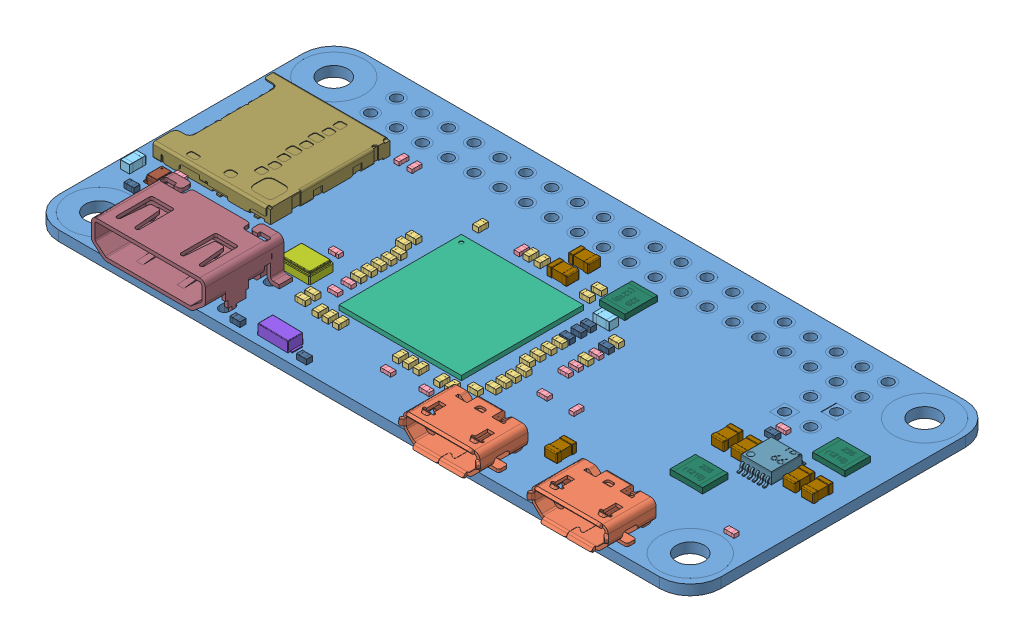
SolidWorks assembly RapberryPiZero, configuration Default. Lengths in mm.
Overall size (65 4.45 31.23).
81 component instances, 15 part files, 154 mates.
Components (placement in the parent):
- Raspberry_pizero_PCB-1: Raspberry_pizero_PCB [Default] at (-51.2564 20.0966 13.0542) size (65 1 30)
- Micro USB_input_female (short)-SMT-1: Micro USB_input_female (short)-SMT [Default] at (-42.3564 22.3216 26.5042) size (7.98 2.94 5.43)
- Micro USB_input_female (short)-SMT-2: Micro USB_input_female (short)-SMT [Default] at (-29.7564 22.3216 26.5042) size (7.98 2.94 5.43)
- 0204 - Capacitor-1: 0204 - Capacitor [Default] at (-62.4121 21.3466 11.2398) size (1 0.5 0.6)
- 0204 - Capacitor-2: 0204 - Capacitor [Default] at (-62.4121 21.3466 12.2528) size (1 0.5 0.6)
- 0204 - Capacitor-3: 0204 - Capacitor [Default] at (-61.8122 21.3466 13.3136) size (1 0.5 0.6)
- 0204 - Capacitor-4: 0204 - Capacitor [Default] at (-61.8122 21.3466 14.2646) size (1 0.5 0.6)
- 0204 - Capacitor-5: 0204 - Capacitor [Default] at (-61.8122 21.3466 15.241) size (1 0.5 0.6)
- 0204 - Capacitor-6: 0204 - Capacitor [Default] at (-61.8122 21.3466 16.2144) size (1 0.5 0.6)
- 0204 - Capacitor-7: 0204 - Capacitor [Default] at (-61.8122 21.3466 17.2416) size (1 0.5 0.6)
- 0204 - Capacitor-8: 0204 - Capacitor [Default] at (-62.5919 21.3466 20.9695) size (1 0.5 0.6)
- 0204 - Capacitor-9: 0204 - Capacitor [Default] at (-62.5919 21.3466 21.919) size (1 0.5 0.6)
- 0204 - Capacitor-10: 0204 - Capacitor [Default] at (-60.4584 21.3466 22.3712) x (0 0 1) z (-1 0 0) size (1 0.5 0.6)
- 0204 - Capacitor-11: 0204 - Capacitor [Default] at (-60.0807 21.3466 22.3712) x (0 0 -1) z (1 0 0) size (1 0.5 0.6)
- 0204 - Capacitor-12: 0204 - Capacitor [Default] at (-59.0466 21.3466 22.3712) x (0 0 -1) z (1 0 0) size (1 0.5 0.6)
- 0204 - Capacitor-13: 0204 - Capacitor [Default] at (-52.6496 21.3466 22.316) x (0 0 1) z (-1 0 0) size (1 0.5 0.6)
- 0204 - Capacitor-14: 0204 - Capacitor [Default] at (-52.25 21.3466 22.316) x (0 0 -1) z (1 0 0) size (1 0.5 0.6)
- 0204 - Capacitor-15: 0204 - Capacitor [Default] at (-51.2398 21.3466 22.316) x (0 0 -1) z (1 0 0) size (1 0.5 0.6)
- 0204 - Capacitor-16: 0204 - Capacitor [Default] at (-49.1841 21.3466 22.316) x (0 0 -1) z (1 0 0) size (1 0.5 0.6)
- 0204 - Capacitor-17: 0204 - Capacitor [Default] at (-48.1448 21.3466 22.316) x (0 0 -1) z (1 0 0) size (1 0.5 0.6)
- 0204 - Capacitor-18: 0204 - Capacitor [Default] at (-46.475 21.3466 21.113) size (1 0.5 0.6)
- 0204 - Capacitor-19: 0204 - Capacitor [Default] at (-45.7322 21.3466 20.0663) size (1 0.5 0.6)
- 0204 - Capacitor-20: 0204 - Capacitor [Default] at (-45.7322 21.3466 19.0675) size (1 0.5 0.6)
- 0204 - Capacitor-21: 0204 - Capacitor [Default] at (-45.7322 21.3466 18.1249) size (1 0.5 0.6)
- 0204 - Capacitor-22: 0204 - Capacitor [Default] at (-45.7322 21.3466 17.1095) size (1 0.5 0.6)
- 0204 - Capacitor-23: 0204 - Capacitor [Default] at (-46.3457 21.3466 16.1412) size (1 0.5 0.6)
- 0204 - Capacitor-24: 0204 - Capacitor [Default] at (-46.3457 21.3466 15.1229) size (1 0.5 0.6)
- 0204 - Capacitor-25: 0204 - Capacitor [Default] at (-46.3457 21.3466 14.0197) size (1 0.5 0.6)
- 0204 - Capacitor-26: 0204 - Capacitor [Default] at (-46.3457 21.3466 12.9589) size (1 0.5 0.6)
- 0204 - Capacitor-27: 0204 - Capacitor [Default] at (-43.6156 21.3466 13.1418) size (1 0.5 0.6)
- 0204 - Capacitor-28: 0204 - Capacitor [Default] at (-43.6156 21.3466 10.1424) size (1 0.5 0.6)
- 0204 - Capacitor-29: 0204 - Capacitor [Default] at (-48.9117 21.3466 7.6917) size (1 0.5 0.6)
- 0204 - Capacitor-30: 0204 - Capacitor [Default] at (-55.4926 21.3466 7.2526) x (0 0 -1) z (1 0 0) size (1 0.5 0.6)
- 0204 - Capacitor-31: 0204 - Capacitor [Default] at (-53.7932 21.3466 7.2526) x (0 0 1) z (-1 0 0) size (1 0.5 0.6)
- 0204 - Capacitor-32: 0204 - Capacitor [Default] at (-59.8477 21.3466 7.2526) x (0 0 1) z (-1 0 0) size (1 0.5 0.6)
- 0204- Resistor-15: 0204- Resistor [Default] at (-43.6109 21.4522 15.4193) x (-1 0 0) z (0 -1 0) size (0.99 0.51 0.36)
- 0204- Resistor-14: 0204- Resistor [Default] at (-43.6109 21.4522 14.4127) x (-1 0 0) z (0 -1 0) size (0.99 0.51 0.36)
- 0204- Resistor-13: 0204- Resistor [Default] at (-43.6109 21.4522 12.4047) x (-1 0 0) z (0 -1 0) size (0.99 0.51 0.36)
- 0204- Resistor-4: 0204- Resistor [Default] at (-42.6936 21.4522 18.4076) x (-1 0 0) z (0 -1 0) size (0.99 0.51 0.36)
- 0204- Resistor-5: 0204- Resistor [Default] at (-39.831 21.4522 18.1462) x (0 0 1) z (0 -1 0) size (0.99 0.51 0.36)
- 0204- Resistor-7: 0204- Resistor [Default] at (-61.8169 21.4522 19.8533) x (-1 0 0) z (0 -1 0) size (0.99 0.51 0.36)
- 0204- Resistor-8: 0204- Resistor [Default] at (-61.8169 21.4522 18.5178) x (-1 0 0) z (0 -1 0) size (0.99 0.51 0.36)
- 0204- Resistor-9: 0204- Resistor [Default] at (-79.148 21.4522 17.7279) x (-1 0 0) z (0 -1 0) size (0.99 0.51 0.36)
- 0204- Resistor-10: 0204- Resistor [Default] at (-56.0985 21.4522 7.2479) x (0 0 -1) z (0 -1 0) size (0.99 0.51 0.36)
- 0204- Resistor-11: 0204- Resistor [Default] at (-28.0827 21.4522 9.5819) x (-1 0 0) z (0 -1 0) size (0.99 0.51 0.36)
- 0204- Resistor-12: 0204- Resistor [Default] at (-21.8613 21.4522 20.9026) x (-1 0 0) z (0 -1 0) size (0.99 0.51 0.36)
- CAP-0306-1: CAP-0306 [Default] at (-45.8903 21.4966 8.7634) size (1.6 0.8 0.9)
- CAP-0306-2: CAP-0306 [Default] at (-82.0031 21.4966 19.0464) x (0 0 1) z (-1 0 0) size (1.6 0.8 0.9)
- Raspberry_pizero_BCM2835 with VC4-2: Raspberry_pizero_BCM2835 with VC4 [Default] at (-54.1608 21.5466 15.1238) x (1 0 0) z (0 0 -1) size (12 0.65 12)
- Crystal 3.4x2.4mm-1: Crystal 3.4x2.4mm [Default] at (-65.3089 21.0966 19.2633) size (3.2 1 2.4)
- 0204- Resistor-16: 0204- Resistor [Default] at (-68.4329 21.4522 5.4384) x (0 0 1) z (0 -1 0) size (0.99 0.51 0.36)
- 0204- Resistor-17: 0204- Resistor [Default] at (-69.7255 21.4522 5.4384) x (0 0 1) z (0 -1 0) size (0.99 0.51 0.36)
- 0204- Resistor-18: 0204- Resistor [Default] at (-65.0626 21.4522 16.5355) x (1 0 0) z (0 -1 0) size (0.99 0.51 0.36)
- 32,768 Khz Crystal-1: 32,768 Khz Crystal [Default] at (-60.5154 21.1428 26.5473) x (0.999848 -0.017452 0) z (0 0 1) size (3.4 1.03 1.5)
- 0805- Capacitor-1: 0805- Capacitor [Default] at (-51.9496 21.9966 5.2384) x (1 0 0) z (0 -1 0) size (2 1.25 0.9)
- 0805- Capacitor-2: 0805- Capacitor [Default] at (-51.9496 21.9966 7.3589) x (1 0 0) z (0 -1 0) size (2 1.25 0.9)
- 0805- Capacitor-3: 0805- Capacitor [Default] at (-37.009 21.9966 22.5384) x (0 0 -1) z (0 -1 0) size (2 1.25 0.9)
- 0805- Capacitor-4: 0805- Capacitor [Default] at (-29.8247 21.9966 13.3538) x (0 0 1) z (0 -1 0) size (2 1.25 0.9)
- 0805- Capacitor-5: 0805- Capacitor [Default] at (-27.9052 21.9966 13.3538) x (0 0 -1) z (0 -1 0) size (2 1.25 0.9)
- 0805- Capacitor-6: 0805- Capacitor [Default] at (-22.8003 21.9966 13.3538) x (0 0 -1) z (0 -1 0) size (2 1.25 0.9)
- 0805- Capacitor-7: 0805- Capacitor [Default] at (-20.9924 21.9966 13.3538) x (0 0 -1) z (0 -1 0) size (2 1.25 0.9)
- 0204- Resistor-19: 0204- Resistor [Default] at (-48.8769 21.4522 23.8207) x (1 0 0) z (0 -1 0) size (0.99 0.51 0.36)
- 0204- Resistor-20: 0204- Resistor [Default] at (-52.4165 21.4522 24.0419) x (1 0 0) z (0 -1 0) size (0.99 0.51 0.36)
- 0204 - Capacitor-33: 0204 - Capacitor [Default] at (-47.1199 21.3466 23.926) x (0 0 1) z (-1 0 0) size (1 0.5 0.6)
- 0204 - Capacitor Brown-34: 0204 - Capacitor Brown [Default] at (-57.5817 21.3466 26.803) size (1 0.5 0.6)
- 0204 - Capacitor Brown-35: 0204 - Capacitor Brown [Default] at (-64.0312 21.3466 26.8794) size (1 0.5 0.6)
- 0204 - Capacitor Brown-36: 0204 - Capacitor Brown [Default] at (-46.3457 21.3466 12.214) size (1 0.5 0.6)
- 0204 - Capacitor Brown-37: 0204 - Capacitor Brown [Default] at (-46.3457 21.3466 11.0963) size (1 0.5 0.6)
- 0204 - Capacitor Brown-38: 0204 - Capacitor Brown [Default] at (-46.3457 21.3466 10.1566) size (1 0.5 0.6)
- 0204 - Capacitor Brown-39: 0204 - Capacitor Brown [Default] at (-43.6156 21.3466 11.1151) size (1 0.5 0.6)
- 0204 - Capacitor Brown-40: 0204 - Capacitor Brown [Default] at (-28.0874 21.3466 10.3236) size (1 0.5 0.6)
- 0204 - Capacitor Brown-41: 0204 - Capacitor Brown [Default] at (-80.6197 21.3466 20.6997) size (1 0.5 0.6)
- 0204- Resistor-21: 0204- Resistor [Default] at (-78.9105 21.4522 21.1554) x (1 0 0) z (0 -1 0) size (0.99 0.51 0.36)
- 6-Pin SOT-1: 6-Pin SOT [Default] at (-79.714 21.0966 19.2138) x (0 0 1) z (0 1 0) size (1.5 1.84 0.95)
- micro sd molex-1: micro sd molex [Default] at (-74.7768 21.6766 -33.0961) x (0 0 1) z (0 1 0) size (11.95 11.4 1.45)
- hdmi type C-1: hdmi type C [Default] at (-71.3564 22.9466 28.6542) size (12.9 4.05 7.7)
- Voltage Regulator 3x3mm 12-Pin-1: Voltage Regulator 3x3mm 12-Pin [Default] at (-23.6842 21.0966 12.6105) x (1 0 0) z (0 1 0) size (3 4.1 1.2)
- 1210 inductor-1: 1210 inductor [Default] at (-46.4963 21.0916 6.3909) x (0 0 1) z (0 1 0) size (3.26 2.86 0.75)
- 1210 inductor-2: 1210 inductor [Default] at (-22.7405 21.0916 9.2394) x (1 0 0) z (0 1 0) size (3.26 2.86 0.75)
- 1210 inductor-3: 1210 inductor [Default] at (-28.2854 21.0916 17.6682) x (1 0 0) z (0 1 0) size (3.26 2.86 0.75)
- 0204 - Capacitor-34: 0204 - Capacitor [Default] at (-48.9117 21.3466 6.5273) size (1 0.5 0.6)
Mates (geometry in assembly coordinates):
- Coincident1: coincident: plane of Raspberry_pizero_PCB-1 through (-80.7564 21.0966 1.0542) normal (0 1 0); plane of Micro USB_input_female (short)-SMT-1 through (-46.4124 21.0966 24.1966) normal (0 -1 0)
- Coincident2: coincident: plane of Raspberry_pizero_PCB-1 through (-80.7564 21.0966 1.0542) normal (0 1 0); plane of Micro USB_input_female (short)-SMT-2 through (-33.8124 21.0966 24.1966) normal (0 -1 0)
- Coincident3: coincident: plane of 0204 - Capacitor-13 through (-52.9516 21.5916 22.316) normal (0 1 0); plane of 0204 - Capacitor-14 through (-51.948 21.5916 22.316) normal (0 1 0)
- Coincident4: coincident: plane of 0204 - Capacitor-14 through (-51.948 21.5916 22.316) normal (0 1 0); plane of 0204 - Capacitor-15 through (-50.9378 21.5916 22.316) normal (0 1 0)
- Coincident5: coincident: plane of 0204 - Capacitor-15 through (-50.9378 21.5916 22.316) normal (0 1 0); plane of 0204 - Capacitor-16 through (-48.8821 21.5916 22.316) normal (0 1 0)
- Coincident6: coincident: plane of 0204 - Capacitor-16 through (-48.8821 21.5916 22.316) normal (0 1 0); plane of 0204 - Capacitor-17 through (-47.8428 21.5916 22.316) normal (0 1 0)
- Coincident7: coincident: plane of 0204 - Capacitor-17 through (-47.8428 21.5916 22.316) normal (0 1 0); plane of 0204 - Capacitor-18 through (-46.475 21.5916 21.415) normal (0 1 0)
- Coincident8: coincident: plane of 0204 - Capacitor-18 through (-46.475 21.5916 21.415) normal (0 1 0); plane of 0204 - Capacitor-19 through (-45.7322 21.5916 20.3683) normal (0 1 0)
- Coincident9: coincident: plane of 0204 - Capacitor-19 through (-45.7322 21.5916 20.3683) normal (0 1 0); plane of 0204 - Capacitor-20 through (-45.7322 21.5916 19.3695) normal (0 1 0)
- Coincident10: coincident: plane of 0204 - Capacitor-20 through (-45.7322 21.5916 19.3695) normal (0 1 0); plane of 0204 - Capacitor-21 through (-45.7322 21.5916 18.4269) normal (0 1 0)
- Coincident11: coincident: plane of 0204 - Capacitor-21 through (-45.7322 21.5916 18.4269) normal (0 1 0); plane of 0204 - Capacitor-22 through (-45.7322 21.5916 17.4115) normal (0 1 0)
- Coincident12: coincident: plane of 0204 - Capacitor-22 through (-45.7322 21.5916 17.4115) normal (0 1 0); plane of 0204 - Capacitor-23 through (-46.3457 21.5916 16.4432) normal (0 1 0)
- Coincident13: coincident: plane of 0204 - Capacitor-23 through (-46.3457 21.5916 16.4432) normal (0 1 0); plane of 0204 - Capacitor-24 through (-46.3457 21.5916 15.4249) normal (0 1 0)
- Coincident14: coincident: plane of 0204 - Capacitor-24 through (-46.3457 21.5916 15.4249) normal (0 1 0); plane of 0204 - Capacitor-25 through (-46.3457 21.5916 14.3217) normal (0 1 0)
- Coincident15: coincident: plane of 0204 - Capacitor-25 through (-46.3457 21.5916 14.3217) normal (0 1 0); plane of 0204 - Capacitor-26 through (-46.3457 21.5916 13.2609) normal (0 1 0)
- Coincident16: coincident: plane of 0204 - Capacitor-26 through (-46.3457 21.5916 13.2609) normal (0 1 0); plane of 0204 - Capacitor-27 through (-43.6156 21.5916 13.4438) normal (0 1 0)
- Coincident17: coincident: plane of 0204 - Capacitor-27 through (-43.6156 21.5916 13.4438) normal (0 1 0); plane of 0204 - Capacitor-28 through (-43.6156 21.5916 10.4444) normal (0 1 0)
- Coincident18: coincident: plane of 0204 - Capacitor-28 through (-43.6156 21.5916 10.4444) normal (0 1 0); plane of 0204 - Capacitor-29 through (-48.9117 21.5916 7.9937) normal (0 1 0)
- Coincident19: coincident: plane of 0204 - Capacitor-29 through (-48.9117 21.5916 7.9937) normal (0 1 0); plane of 0204 - Capacitor-31 through (-54.0952 21.5916 7.2526) normal (0 1 0)
- Coincident20: coincident: plane of 0204 - Capacitor-30 through (-55.1906 21.5916 7.2526) normal (0 1 0); plane of 0204 - Capacitor-31 through (-54.0952 21.5916 7.2526) normal (0 1 0)
- Coincident21: coincident: plane of 0204 - Capacitor-30 through (-55.1906 21.5916 7.2526) normal (0 1 0); plane of 0204 - Capacitor-32 through (-60.1497 21.5916 7.2526) normal (0 1 0)
- Coincident22: coincident: plane of 0204 - Capacitor-1 through (-62.4121 21.5916 11.5418) normal (0 1 0); plane of 0204 - Capacitor-32 through (-60.1497 21.5916 7.2526) normal (0 1 0)
- Coincident23: coincident: plane of 0204 - Capacitor-1 through (-62.4121 21.5916 11.5418) normal (0 1 0); plane of 0204 - Capacitor-2 through (-62.4121 21.5916 12.5548) normal (0 1 0)
- Coincident24: coincident: plane of 0204 - Capacitor-2 through (-62.4121 21.5916 12.5548) normal (0 1 0); plane of 0204 - Capacitor-3 through (-61.8122 21.5916 13.6156) normal (0 1 0)
- Coincident25: coincident: plane of 0204 - Capacitor-3 through (-61.8122 21.5916 13.6156) normal (0 1 0); plane of 0204 - Capacitor-4 through (-61.8122 21.5916 14.5666) normal (0 1 0)
- Coincident26: coincident: plane of 0204 - Capacitor-4 through (-61.8122 21.5916 14.5666) normal (0 1 0); plane of 0204 - Capacitor-5 through (-61.8122 21.5916 15.543) normal (0 1 0)
- Coincident27: coincident: plane of 0204 - Capacitor-5 through (-61.8122 21.5916 15.543) normal (0 1 0); plane of 0204 - Capacitor-6 through (-61.8122 21.5916 16.5164) normal (0 1 0)
- Coincident28: coincident: plane of 0204 - Capacitor-6 through (-61.8122 21.5916 16.5164) normal (0 1 0); plane of 0204 - Capacitor-7 through (-61.8122 21.5916 17.5436) normal (0 1 0)
- Coincident29: coincident: plane of 0204 - Capacitor-7 through (-61.8122 21.5916 17.5436) normal (0 1 0); plane of 0204 - Capacitor-8 through (-62.5919 21.5916 21.2715) normal (0 1 0)
- Coincident30: coincident: plane of 0204 - Capacitor-8 through (-62.5919 21.5916 21.2715) normal (0 1 0); plane of 0204 - Capacitor-9 through (-62.5919 21.5916 22.221) normal (0 1 0)
- Coincident31: coincident: plane of 0204 - Capacitor-9 through (-62.5919 21.5916 22.221) normal (0 1 0); plane of 0204 - Capacitor-10 through (-60.7604 21.5916 22.3712) normal (0 1 0)
- Coincident32: coincident: plane of 0204 - Capacitor-10 through (-60.7604 21.5916 22.3712) normal (0 1 0); plane of 0204 - Capacitor-11 through (-59.7787 21.5916 22.3712) normal (0 1 0)
- Coincident33: coincident: plane of 0204 - Capacitor-11 through (-59.7787 21.5916 22.3712) normal (0 1 0); plane of 0204 - Capacitor-12 through (-58.7446 21.5916 22.3712) normal (0 1 0)
- Coincident34: coincident: plane of Raspberry_pizero_PCB-1 through (-80.7564 21.0966 1.0542) normal (0 1 0); plane of 0204 - Capacitor-9 through (-62.9669 21.0966 22.219) normal (0 -1 0)
- Coincident35: coincident: plane of 0204 - Capacitor-25 through (-46.8457 21.0966 14.3197) normal (-1 0 0); plane of 0204 - Capacitor-26 through (-46.8457 21.0966 13.2589) normal (-1 0 0)
- Coincident36: coincident: plane of 0204 - Capacitor-24 through (-46.8457 21.0966 15.4229) normal (-1 0 0); plane of 0204 - Capacitor-25 through (-46.8457 21.0966 14.3197) normal (-1 0 0)
- Coincident37: coincident: plane of 0204 - Capacitor-23 through (-46.8457 21.0966 16.4412) normal (-1 0 0); plane of 0204 - Capacitor-24 through (-46.8457 21.0966 15.4229) normal (-1 0 0)
- Coincident38: coincident: plane of 0204 - Capacitor-27 through (-44.1156 21.0966 13.4418) normal (-1 0 0); plane of 0204 - Capacitor-28 through (-44.1156 21.0966 10.4424) normal (-1 0 0)
- Parallel1: parallel: plane of Raspberry_pizero_PCB-1 through (-80.7564 21.0966 -1.9458) normal (0 0 -1); plane of 0204 - Capacitor-30 through (-55.1926 21.0966 7.7526) normal (0 0 1)
- Coincident39: coincident: plane of 0204 - Capacitor-30 through (-55.1926 21.0966 6.7526) normal (0 0 -1); plane of 0204 - Capacitor-31 through (-54.0932 21.0966 6.7526) normal (0 0 -1)
- Coincident40: coincident: plane of 0204 - Capacitor-30 through (-55.1926 21.0966 6.7526) normal (0 0 -1); plane of 0204 - Capacitor-32 through (-60.1477 21.0966 6.7526) normal (0 0 -1)
- Coincident41: coincident: plane of 0204 - Capacitor-1 through (-62.9121 21.0966 11.5398) normal (-1 0 0); plane of 0204 - Capacitor-2 through (-62.9121 21.0966 12.5528) normal (-1 0 0)
- Coincident42: coincident: plane of 0204 - Capacitor-3 through (-62.3122 21.0966 13.6136) normal (-1 0 0); plane of 0204 - Capacitor-4 through (-62.3122 21.0966 14.5646) normal (-1 0 0)
- Coincident43: coincident: plane of 0204 - Capacitor-4 through (-62.3122 21.0966 14.5646) normal (-1 0 0); plane of 0204 - Capacitor-5 through (-62.3122 21.0966 15.541) normal (-1 0 0)
- Coincident44: coincident: plane of 0204 - Capacitor-5 through (-62.3122 21.0966 15.541) normal (-1 0 0); plane of 0204 - Capacitor-6 through (-62.3122 21.0966 16.5144) normal (-1 0 0)
- Coincident45: coincident: plane of 0204 - Capacitor-6 through (-62.3122 21.0966 16.5144) normal (-1 0 0); plane of 0204 - Capacitor-7 through (-62.3122 21.0966 17.5416) normal (-1 0 0)
- Coincident46: coincident: plane of 0204 - Capacitor-8 through (-63.0919 21.0966 21.2695) normal (-1 0 0); plane of 0204 - Capacitor-9 through (-63.0919 21.0966 22.219) normal (-1 0 0)
- Parallel2: parallel: plane of Raspberry_pizero_PCB-1 through (-80.7564 21.0966 28.0542) normal (0 0 1); plane of 0204 - Capacitor-10 through (-60.7584 21.0966 21.8712) normal (0 0 -1)
- Coincident48: coincident: plane of 0204 - Capacitor-10 through (-60.7584 21.0966 22.8712) normal (0 0 1); plane of 0204 - Capacitor-11 through (-59.7807 21.0966 22.8712) normal (0 0 1)
- Coincident49: coincident: plane of 0204 - Capacitor-11 through (-59.7807 21.0966 22.8712) normal (0 0 1); plane of 0204 - Capacitor-12 through (-58.7466 21.0966 22.8712) normal (0 0 1)
- Parallel3: parallel: plane of Raspberry_pizero_PCB-1 through (-80.7564 21.0966 28.0542) normal (0 0 1); plane of 0204 - Capacitor-13 through (-52.9496 21.0966 21.816) normal (0 0 -1)
- Coincident51: coincident: plane of 0204 - Capacitor-13 through (-52.9496 21.0966 22.816) normal (0 0 1); plane of 0204 - Capacitor-14 through (-51.95 21.0966 22.816) normal (0 0 1)
- Coincident52: coincident: plane of 0204 - Capacitor-14 through (-51.95 21.0966 22.816) normal (0 0 1); plane of 0204 - Capacitor-15 through (-50.9398 21.0966 22.816) normal (0 0 1)
- Coincident53: coincident: plane of 0204 - Capacitor-15 through (-50.9398 21.0966 22.816) normal (0 0 1); plane of 0204 - Capacitor-16 through (-48.8841 21.0966 22.816) normal (0 0 1)
- Coincident54: coincident: plane of 0204 - Capacitor-16 through (-48.8841 21.0966 22.816) normal (0 0 1); plane of 0204 - Capacitor-17 through (-47.8448 21.0966 22.816) normal (0 0 1)
- Parallel7: parallel: plane of Raspberry_pizero_PCB-1 through (-80.7564 21.0966 28.0542) normal (0 0 1); plane of CAP-0306-2 through (-82.4531 21.0966 18.2464) normal (0 0 -1)
- Parallel8: parallel: plane of Raspberry_pizero_PCB-1 through (-18.7564 21.0966 25.0542) normal (1 0 0); plane of CAP-0306-1 through (-45.0903 21.0966 9.2134) normal (1 0 0)
- Coincident77: coincident: plane of 0204 - Capacitor-21 through (-46.2322 21.0966 18.4249) normal (-1 0 0); plane of 0204 - Capacitor-22 through (-46.2322 21.0966 17.4095) normal (-1 0 0)
- Coincident78: coincident: plane of 0204 - Capacitor-20 through (-46.2322 21.0966 19.3675) normal (-1 0 0); plane of 0204 - Capacitor-21 through (-46.2322 21.0966 18.4249) normal (-1 0 0)
- Coincident79: coincident: plane of 0204 - Capacitor-19 through (-46.2322 21.0966 20.3663) normal (-1 0 0); plane of 0204 - Capacitor-20 through (-46.2322 21.0966 19.3675) normal (-1 0 0)
- Coincident80: coincident: plane of Micro USB_input_female (short)-SMT-1 through (-39.2364 21.3596 23.1542) normal (0 0 -1); plane of Micro USB_input_female (short)-SMT-2 through (-26.6364 21.3596 23.1542) normal (0 0 -1)
- Distance1: distance = 41.4 mm: moEndPointRef_w of Micro USB_input_female (short)-SMT-1; plane of Raspberry_pizero_PCB-1 through (-83.7564 21.0966 25.0542) normal (-1 0 0)
- Distance3: distance = 0.8 mm: plane of Micro USB_input_female (short)-SMT-1 through (-46.2564 21.0476 28.8542) normal (0 0 1); plane of Raspberry_pizero_PCB-1 through (-80.7564 21.0966 28.0542) normal (0 0 1)
- Distance4: distance = 54 mm: moEndPointRef_w of Micro USB_input_female (short)-SMT-2; plane of Raspberry_pizero_PCB-1 through (-83.7564 21.0966 25.0542) normal (-1 0 0)
- Coincident86: coincident: plane of Raspberry_pizero_PCB-1 through (-80.7564 21.0966 1.0542) normal (0 1 0); plane of Raspberry_pizero_BCM2835 with VC4-2 through (-54.1608 21.0966 15.1238) normal (0 -1 0)
- Parallel10: parallel: plane of Raspberry_pizero_BCM2835 with VC4-2 through (-60.1608 21.0966 9.1238) normal (0 0 -1); plane of Raspberry_pizero_PCB-1 through (-80.7564 21.0966 28.0542) normal (0 0 1)
- Coincident88: coincident: plane of Raspberry_pizero_PCB-1 through (-80.7564 21.0966 1.0542) normal (0 1 0); plane of CAP-0306-1 through (-45.2653 21.0966 9.2134) normal (0 -1 0)
- Coincident89: coincident: plane of 0204- Resistor-7 through (-61.5248 21.0966 19.5993) normal (0 -1 0); plane of 0204- Resistor-8 through (-61.5248 21.0966 18.2638) normal (0 -1 0)
- Coincident90: coincident: plane of Raspberry_pizero_PCB-1 through (-80.7564 21.0966 1.0542) normal (0 1 0); plane of 0204- Resistor-8 through (-61.5248 21.0966 18.2638) normal (0 -1 0)
- Parallel11: parallel: plane of Raspberry_pizero_PCB-1 through (-80.7564 21.0966 28.0542) normal (0 0 1); plane of 0204 - Capacitor-7 through (-61.8122 21.1016 17.8406) normal (0 0 1)
- Coincident92: coincident: plane of 0204 - Capacitor-7 through (-62.3122 21.0966 17.5416) normal (-1 0 0); plane of 0204- Resistor-8 through (-62.3122 21.0966 18.2638) normal (-1 0 0)
- Coincident93: coincident: plane of 0204- Resistor-7 through (-62.3122 21.0966 19.5993) normal (-1 0 0); plane of 0204- Resistor-8 through (-62.3122 21.0966 18.2638) normal (-1 0 0)
- Coincident94: coincident: plane of 0204 - Capacitor-30 through (-55.1926 21.0966 6.7526) normal (0 0 -1); plane of 0204- Resistor-10 through (-55.8445 21.0966 6.7526) normal (0 0 -1)
- Coincident95: coincident: plane of Raspberry_pizero_PCB-1 through (-80.7564 21.0966 1.0542) normal (0 1 0); plane of 0204- Resistor-10 through (-55.8445 21.0966 6.9558) normal (0 -1 0)
- Coincident96: coincident: plane of 0204- Resistor-14 through (-43.903 21.0966 14.1587) normal (0 -1 0); plane of 0204- Resistor-13 through (-43.903 21.0966 12.1507) normal (0 -1 0)
- Coincident97: coincident: plane of 0204- Resistor-15 through (-43.903 21.0966 15.1653) normal (0 -1 0); plane of 0204- Resistor-14 through (-43.903 21.0966 14.1587) normal (0 -1 0)
- Coincident98: coincident: plane of 0204- Resistor-15 through (-43.903 21.0966 15.1653) normal (0 -1 0); plane of 0204- Resistor-4 through (-42.9857 21.0966 18.1536) normal (0 -1 0)
- Coincident99: coincident: plane of Raspberry_pizero_PCB-1 through (-80.7564 21.0966 1.0542) normal (0 1 0); plane of 0204- Resistor-15 through (-43.903 21.0966 15.1653) normal (0 -1 0)
- Coincident101: coincident: plane of 0204- Resistor-5 through (-40.085 21.0966 18.4383) normal (0 -1 0); plane of 0204- Resistor-11 through (-27.7906 21.0966 9.3279) normal (0 -1 0)
- Coincident102: coincident: plane of 0204- Resistor-11 through (-27.7906 21.0966 9.3279) normal (0 -1 0); plane of 0204- Resistor-12 through (-21.5692 21.0966 20.6486) normal (0 -1 0)
- Coincident103: coincident: plane of Raspberry_pizero_PCB-1 through (-80.7564 21.0966 1.0542) normal (0 1 0); plane of Crystal 3.4x2.4mm-1 through (-65.3089 21.0966 19.2633) normal (0 -1 0)
- Parallel12: parallel: plane of Raspberry_pizero_PCB-1 through (-80.7564 21.0966 28.0542) normal (0 0 1); plane of Crystal 3.4x2.4mm-1 through (-66.9089 21.7966 20.4633) normal (0 0 1)
- Coincident104: coincident: plane of Raspberry_pizero_PCB-1 through (-80.7564 21.0966 1.0542) normal (0 1 0); plane of 0204- Resistor-9 through (-78.8559 21.0966 17.4739) normal (0 -1 0)
- Parallel13: parallel: plane of Raspberry_pizero_PCB-1 through (-80.7564 21.0966 28.0542) normal (0 0 1); plane of 0204- Resistor-9 through (-78.2985 21.4532 17.9829) normal (0 0 1)
- Coincident105: coincident: plane of Raspberry_pizero_PCB-1 through (-80.7564 21.0966 1.0542) normal (0 1 0); plane of CAP-0306-2 through (-82.4531 21.0966 19.6714) normal (0 -1 0)
- Coincident106: coincident: plane of 0204 - Capacitor-28 through (-43.1156 21.0966 10.4424) normal (1 0 0); plane of 0204- Resistor-13 through (-43.1156 21.0966 12.1507) normal (1 0 0)
- Coincident107: coincident: plane of 0204 - Capacitor-27 through (-43.1156 21.0966 13.4418) normal (1 0 0); plane of 0204- Resistor-14 through (-43.1156 21.0966 14.1587) normal (1 0 0)
- Parallel14: parallel: plane of Raspberry_pizero_PCB-1 through (-80.7564 21.0966 28.0542) normal (0 0 1); plane of 0204- Resistor-14 through (-42.7614 21.4532 14.6677) normal (0 0 1)
- Coincident110: coincident: plane of 0204- Resistor-15 through (-43.1156 21.0966 15.1653) normal (1 0 0); plane of 0204- Resistor-14 through (-43.1156 21.0966 14.1587) normal (1 0 0)
- Parallel15: parallel: plane of 0204- Resistor-15 through (-43.1156 21.0966 15.1653) normal (1 0 0); plane of 0204- Resistor-4 through (-42.1983 21.0966 18.1536) normal (1 0 0)
- Parallel16: parallel: plane of Raspberry_pizero_PCB-1 through (-80.7564 21.0966 28.0542) normal (0 0 1); plane of 0204- Resistor-5 through (-40.085 21.0966 18.6415) normal (0 0 1)
- Coincident112: coincident: plane of Raspberry_pizero_PCB-1 through (-80.7564 21.0966 1.0542) normal (0 1 0); plane of 0204- Resistor-5 through (-40.085 21.0966 18.4383) normal (0 -1 0)
- Parallel17: parallel: plane of Raspberry_pizero_PCB-1 through (-18.7564 21.0966 25.0542) normal (1 0 0); plane of 0204- Resistor-12 through (-21.366 21.0966 20.6486) normal (1 0 0)
- Parallel18: parallel: plane of 0204- Resistor-11 through (-27.5874 21.0966 9.3279) normal (1 0 0); plane of 0204- Resistor-12 through (-21.366 21.0966 20.6486) normal (1 0 0)
- Coincident115: coincident: plane of Raspberry_pizero_PCB-1 through (-80.7564 21.0966 1.0542) normal (0 1 0); plane of 0204- Resistor-16 through (-68.6869 21.0966 5.1463) normal (0 -1 0)
- Coincident116: coincident: plane of 0204- Resistor-16 through (-68.6879 21.4532 4.5889) normal (0 1 0); plane of 0204- Resistor-17 through (-69.9805 21.4532 4.5889) normal (0 1 0)
- Coincident117: coincident: plane of 0204- Resistor-17 through (-69.9805 21.4532 4.5889) normal (0 1 0); plane of 0204- Resistor-18 through (-65.9121 21.4532 16.7905) normal (0 1 0)
- Coincident118: coincident: plane of 0204- Resistor-16 through (-68.6869 21.0966 5.9337) normal (0 0 1); plane of 0204- Resistor-17 through (-69.9795 21.0966 5.9337) normal (0 0 1)
- Parallel19: parallel: plane of Raspberry_pizero_PCB-1 through (-80.7564 21.0966 -1.9458) normal (0 0 -1); plane of 0204- Resistor-17 through (-69.9795 21.0966 5.9337) normal (0 0 1)
- Parallel20: parallel: plane of Raspberry_pizero_PCB-1 through (-80.7564 21.0966 28.0542) normal (0 0 1); plane of 0204- Resistor-18 through (-65.9121 21.4532 16.7905) normal (0 0 1)
- Coincident120: coincident: plane of Raspberry_pizero_PCB-1 through (-80.7564 21.0966 1.0542) normal (0 1 0); plane of 32,768 Khz Crystal-1 through (-59.5156 21.0966 27.0473) normal (0 -1 0)
- Coincident121: coincident: plane of Raspberry_pizero_PCB-1 through (-80.7564 21.0966 1.0542) normal (0 1 0); plane of 0805- Capacitor-1 through (-52.9496 21.0966 5.8634) normal (0 -1 0)
- Coincident122: coincident: plane of Raspberry_pizero_PCB-1 through (-80.7564 21.0966 1.0542) normal (0 1 0); plane of 0805- Capacitor-2 through (-52.9496 21.0966 7.9839) normal (0 -1 0)
- Coincident123: coincident: plane of Raspberry_pizero_PCB-1 through (-80.7564 21.0966 1.0542) normal (0 1 0); plane of 0805- Capacitor-3 through (-37.634 21.0966 21.5384) normal (0 -1 0)
- Coincident124: coincident: plane of Raspberry_pizero_PCB-1 through (-80.7564 21.0966 1.0542) normal (0 1 0); plane of 0805- Capacitor-4 through (-30.4497 21.0966 12.3538) normal (0 -1 0)
- Coincident125: coincident: plane of Raspberry_pizero_PCB-1 through (-80.7564 21.0966 1.0542) normal (0 1 0); plane of 0805- Capacitor-5 through (-27.2802 21.0966 14.3538) normal (0 -1 0)
- Parallel21: parallel: plane of Raspberry_pizero_PCB-1 through (-80.7564 21.0966 28.0542) normal (0 0 1); plane of 0805- Capacitor-4 through (-29.8247 21.9966 12.3538) normal (0 0 -1)
- Coincident126: coincident: plane of 0805- Capacitor-4 through (-29.8247 21.9966 14.3538) normal (0 0 1); plane of 0805- Capacitor-5 through (-27.9052 21.9966 14.3538) normal (0 0 1)
- Coincident127: coincident: plane of Raspberry_pizero_PCB-1 through (-80.7564 21.0966 1.0542) normal (0 1 0); plane of 0805- Capacitor-6 through (-22.1753 21.0966 14.3538) normal (0 -1 0)
- Coincident128: coincident: plane of Raspberry_pizero_PCB-1 through (-80.7564 21.0966 1.0542) normal (0 1 0); plane of 0805- Capacitor-7 through (-20.3674 21.0966 14.3538) normal (0 -1 0)
- Coincident129: coincident: plane of 0805- Capacitor-5 through (-27.9052 21.9966 14.3538) normal (0 0 1); plane of 0805- Capacitor-6 through (-22.8003 21.9966 14.3538) normal (0 0 1)
- Coincident130: coincident: plane of 0805- Capacitor-6 through (-22.8003 21.9966 14.3538) normal (0 0 1); plane of 0805- Capacitor-7 through (-20.9924 21.9966 14.3538) normal (0 0 1)
- Parallel22: parallel: plane of Raspberry_pizero_PCB-1 through (-80.7564 21.0966 28.0542) normal (0 0 1); plane of 0805- Capacitor-3 through (-37.009 21.9966 21.5384) normal (0 0 -1)
- Coincident131: coincident: plane of 0805- Capacitor-1 through (-50.9496 21.9966 5.2384) normal (1 0 0); plane of 0805- Capacitor-2 through (-50.9496 21.9966 7.3589) normal (1 0 0)
- Parallel23: parallel: plane of Raspberry_pizero_PCB-1 through (-80.7564 21.0966 28.0542) normal (0 0 1); plane of 6-Pin SOT-1 through (-80.214 22.0466 18.4638) normal (0 0 -1)
- Coincident134: coincident: plane of Raspberry_pizero_PCB-1 through (-80.7564 21.0966 1.0542) normal (0 1 0); plane of 6-Pin SOT-1 through (-80.434 21.0966 19.8263) normal (0 -1 0)
- Coincident135: coincident: plane of Raspberry_pizero_PCB-1 through (-80.7564 21.0966 1.0542) normal (0 1 0); plane of micro sd molex-1 through (-71.1444 21.0966 16.7043) normal (0 -1 0)
- Parallel24: parallel: plane of Raspberry_pizero_PCB-1 through (-80.7564 21.0966 -1.9458) normal (0 0 -1); plane of micro sd molex-1 through (-84.5393 22.448 5.3989) normal (0 0 -1)
- Coincident141: coincident: plane of Raspberry_pizero_PCB-1 through (-80.7564 21.0966 1.0542) normal (0 1 0); plane of hdmi type C-1 through (-77.8064 21.0966 20.9542) normal (0 -1 0)
- Distance5: distance = 12.4 mm: moEndPointRef_w of hdmi type C-1; plane of Raspberry_pizero_PCB-1 through (-83.7564 21.0966 25.0542) normal (-1 0 0)
- Distance6: distance = 17.2 mm: moEndPointRef_w of micro sd molex-1; plane of Raspberry_pizero_PCB-1 through (-80.7564 21.0966 28.0542) normal (0 0 1)
- Parallel25: parallel: plane of Raspberry_pizero_PCB-1 through (-80.7564 21.0966 28.0542) normal (0 0 1); plane of hdmi type C-1 through (-71.3564 22.9466 28.6542) normal (0 0 1)
- Distance7: distance = 0.6 mm: plane of hdmi type C-1 through (-71.3564 22.9466 28.6542) normal (0 0 1); plane of Raspberry_pizero_PCB-1 through (-80.7564 21.0966 28.0542) normal (0 0 1)
- Coincident142: coincident: plane of Raspberry_pizero_PCB-1 through (-80.7564 21.0966 1.0542) normal (0 1 0); plane of 0204 - Capacitor Brown-34 through (-57.9567 21.0966 27.103) normal (0 -1 0)
- Coincident143: coincident: plane of 0204 - Capacitor Brown-34 through (-57.5817 21.5916 27.105) normal (0 1 0); plane of 0204 - Capacitor Brown-35 through (-64.0312 21.5916 27.1814) normal (0 1 0)
- Coincident144: coincident: plane of 0204 - Capacitor-18 through (-46.475 21.5916 21.415) normal (0 1 0); plane of 0204 - Capacitor-33 through (-47.4219 21.5916 23.926) normal (0 1 0)
- Parallel26: parallel: plane of Raspberry_pizero_PCB-1 through (-80.7564 21.0966 28.0542) normal (0 0 1); plane of 0204 - Capacitor-33 through (-47.4199 21.0966 23.426) normal (0 0 -1)
- Coincident146: coincident: plane of Raspberry_pizero_PCB-1 through (-80.7564 21.0966 1.0542) normal (0 1 0); plane of 0204- Resistor-19 through (-48.5848 21.0966 24.0747) normal (0 -1 0)
- Coincident147: coincident: plane of Raspberry_pizero_PCB-1 through (-80.7564 21.0966 1.0542) normal (0 1 0); plane of 0204- Resistor-20 through (-52.1244 21.0966 24.2959) normal (0 -1 0)
- Coincident148: coincident: plane of Raspberry_pizero_PCB-1 through (-80.7564 21.0966 1.0542) normal (0 1 0); plane of 0204- Resistor-21 through (-79.2026 21.0966 21.4094) normal (0 -1 0)
- Coincident149: coincident: plane of Raspberry_pizero_PCB-1 through (-80.7564 21.0966 1.0542) normal (0 1 0); plane of 0204 - Capacitor Brown-41 through (-80.9947 21.0966 20.9997) normal (0 -1 0)
- Parallel27: parallel: plane of Raspberry_pizero_PCB-1 through (-80.7564 21.0966 28.0542) normal (0 0 1); plane of 0204- Resistor-21 through (-78.9105 21.4522 21.4094) normal (0 0 1)
- Parallel28: parallel: plane of Raspberry_pizero_PCB-1 through (-80.7564 21.0966 28.0542) normal (0 0 1); plane of 0204 - Capacitor Brown-41 through (-80.6197 21.1016 21.2987) normal (0 0 1)
- Parallel29: parallel: plane of 0204- Resistor-19 through (-49.7264 21.4532 24.0757) normal (0 0 1); plane of 0204- Resistor-20 through (-53.266 21.4532 24.2969) normal (0 0 1)
- Coincident152: coincident: plane of 0204 - Capacitor Brown-34 through (-57.5817 21.5916 27.105) normal (0 1 0); plane of 0204 - Capacitor Brown-39 through (-43.6156 21.5916 11.4171) normal (0 1 0)
- Coincident153: coincident: plane of 0204 - Capacitor Brown-36 through (-46.3457 21.5916 12.516) normal (0 1 0); plane of 0204 - Capacitor Brown-39 through (-43.6156 21.5916 11.4171) normal (0 1 0)
- Coincident154: coincident: plane of 0204 - Capacitor Brown-36 through (-46.3457 21.5916 12.516) normal (0 1 0); plane of 0204 - Capacitor Brown-37 through (-46.3457 21.5916 11.3983) normal (0 1 0)
- Coincident155: coincident: plane of 0204 - Capacitor Brown-37 through (-46.3457 21.5916 11.3983) normal (0 1 0); plane of 0204 - Capacitor Brown-38 through (-46.3457 21.5916 10.4586) normal (0 1 0)
- Coincident156: coincident: plane of 0204 - Capacitor-26 through (-45.8457 21.0966 13.2589) normal (1 0 0); plane of 0204 - Capacitor Brown-36 through (-45.8457 21.0966 12.514) normal (1 0 0)
- Coincident157: coincident: plane of 0204 - Capacitor Brown-36 through (-45.8457 21.0966 12.514) normal (1 0 0); plane of 0204 - Capacitor Brown-37 through (-45.8457 21.0966 11.3963) normal (1 0 0)
- Coincident158: coincident: plane of 0204 - Capacitor Brown-37 through (-45.8457 21.0966 11.3963) normal (1 0 0); plane of 0204 - Capacitor Brown-38 through (-45.8457 21.0966 10.4566) normal (1 0 0)
- Coincident159: coincident: plane of 0204 - Capacitor-28 through (-43.1156 21.0966 10.4424) normal (1 0 0); plane of 0204 - Capacitor Brown-39 through (-43.1156 21.0966 11.4151) normal (1 0 0)
- Coincident160: coincident: plane of 0204 - Capacitor Brown-39 through (-43.6156 21.5916 11.4171) normal (0 1 0); plane of 0204 - Capacitor Brown-40 through (-28.0874 21.5916 10.6256) normal (0 1 0)
- Coincident161: coincident: plane of 0204- Resistor-11 through (-27.5874 21.0966 9.3279) normal (1 0 0); plane of 0204 - Capacitor Brown-40 through (-27.5874 21.0966 10.6236) normal (1 0 0)
- Coincident163: coincident: plane of Raspberry_pizero_PCB-1 through (-80.7564 21.0966 1.0542) normal (0 1 0); plane of Voltage Regulator 3x3mm 12-Pin-1 through (-24.1342 21.0966 11.3118) normal (0 -1 0)
- Parallel30: parallel: plane of Raspberry_pizero_PCB-1 through (-18.7564 21.0966 25.0542) normal (1 0 0); plane of Voltage Regulator 3x3mm 12-Pin-1 through (-23.9842 22.2966 11.8605) normal (1 0 0)
- Coincident165: coincident: plane of Raspberry_pizero_PCB-1 through (-80.7564 21.0966 1.0542) normal (0 1 0); line of 1210 inductor-2 through (-21.1405 21.0966 7.9944) axis (0 0 1)
- Coincident166: coincident: plane of 1210 inductor-3 through (-28.2854 21.6416 16.4182) normal (0 1 0); plane of 1210 inductor-2 through (-22.7405 21.6416 7.9894) normal (0 1 0)
- Coincident167: coincident: plane of 0204 - Capacitor-29 through (-48.9117 21.5916 7.9937) normal (0 1 0); plane of 0204 - Capacitor-34 through (-48.9117 21.5916 6.8293) normal (0 1 0)
- Coincident168: coincident: plane of 0204 - Capacitor-29 through (-49.4117 21.0966 7.9917) normal (-1 0 0); plane of 0204 - Capacitor-34 through (-49.4117 21.0966 6.8273) normal (-1 0 0)
- Coincident169: coincident: plane of 1210 inductor-1 through (-45.2463 21.6416 6.3909) normal (0 1 0); plane of 1210 inductor-2 through (-22.7405 21.6416 7.9894) normal (0 1 0)
- Parallel31: parallel: plane of Raspberry_pizero_PCB-1 through (-18.7564 21.0966 25.0542) normal (1 0 0); plane of 1210 inductor-2 through (-21.1405 21.3666 10.4894) normal (1 0 0)
- Parallel32: parallel: plane of Raspberry_pizero_PCB-1 through (-18.7564 21.0966 25.0542) normal (1 0 0); plane of 1210 inductor-3 through (-26.6854 21.3666 18.9182) normal (1 0 0)
- Parallel33: parallel: plane of Raspberry_pizero_PCB-1 through (-18.7564 21.0966 25.0542) normal (1 0 0); plane of 1210 inductor-1 through (-45.2468 21.3666 6.3909) normal (1 0 0)
